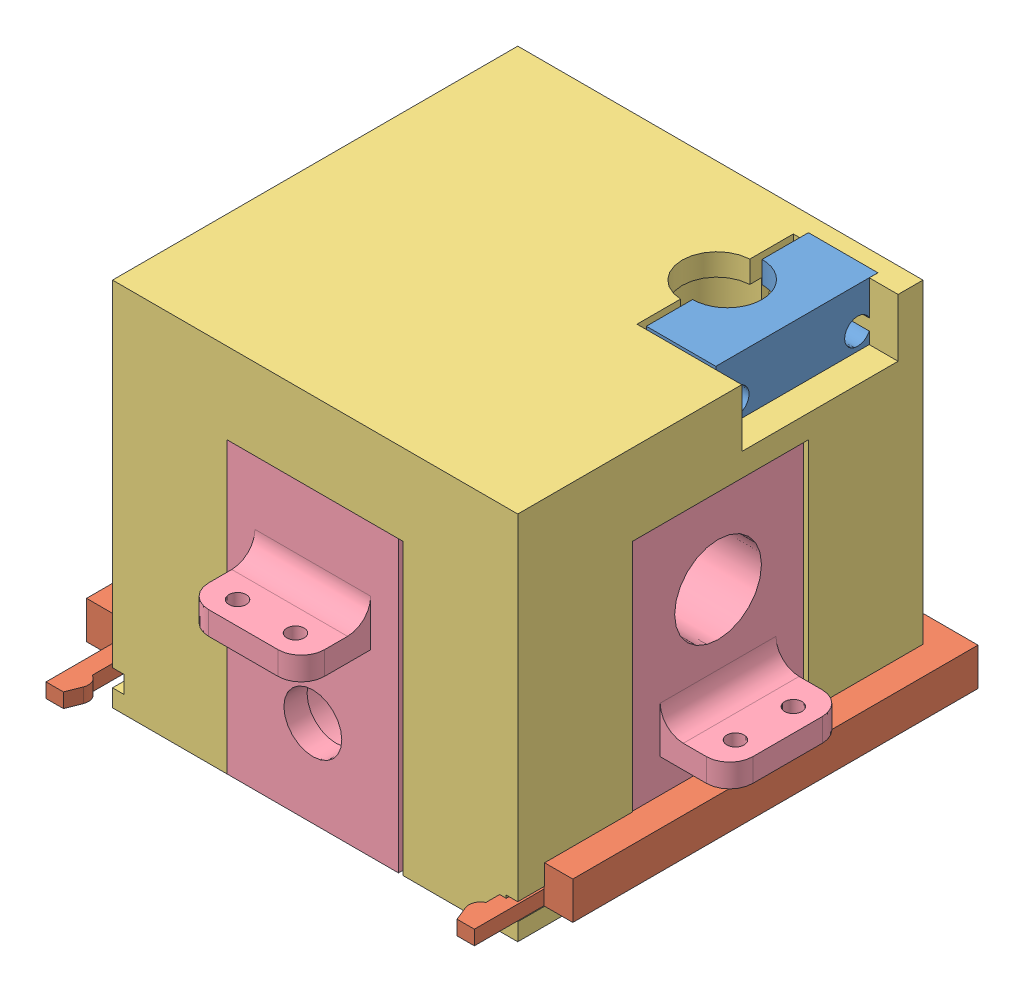
SolidWorks assembly P3DMIPC-Tête_complete, configuration Défaut. Lengths in mm.
Overall size (94 64.01 96.63).
4 component instances, 4 part files, 3 mates.
Components (placement in the parent):
- P3DMIPC-Clip_Buse_E3D-1: P3DMIPC-Clip_Buse_E3D [Défaut] at (17.0518 23.4109 40.0035) x (1 0 0) z (0 1 0) size (12 28 10)
- P3DMIPC-Clip_tête-1: P3DMIPC-Clip_tête [Défaut] at (26.9018 -25.0891 4.5597) x (1 0 0) z (0 -1 0) size (84 92 6.55)
- P3DMIPC-Porte_Buse_E3DX1-1: P3DMIPC-Porte_Buse_E3DX1 [Défaut] at (22.03 33.4019 79.1927) x (0 0 1) z (0 -1 0) size (70 70 64)
- P3DMIPC-Chariot-1: P3DMIPC-Chariot [Défaut] at (-48.37 -30.5981 79.1927) size (94 50 94)
Mates (geometry in assembly coordinates):
- Coïncidente19: coincident anti-aligned: plane of P3DMIPC-Porte_Buse_E3DX1-1 through (22.03 19.4019 79.1927) normal (0 -1 0); plane of P3DMIPC-Chariot-1 through (21.63 19.4019 79.1927) normal (0 1 0)
- Coïncidente20: coincident anti-aligned: plane of P3DMIPC-Porte_Buse_E3DX1-1 through (-28.17 19.4019 79.1927) normal (1 0 0); plane of P3DMIPC-Chariot-1 through (-28.17 19.4019 79.1927) normal (-1 0 0)
- Coïncidente21: coincident aligned: plane of P3DMIPC-Porte_Buse_E3DX1-1 through (22.03 -30.5981 79.1927) normal (0 0 1); plane of P3DMIPC-Chariot-1 through (21.63 -30.5981 79.1927) normal (0 0 1)
